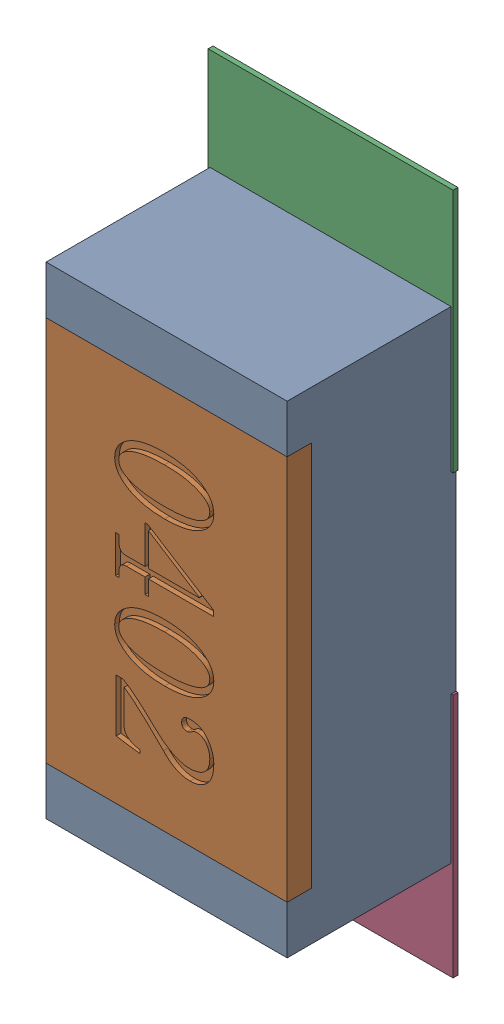
SolidWorks assembly R16, configuration Défaut. Lengths in mm.
Overall size (0.51 1.42 0.35).
5 component instances, 2 part files, 0 mates.
Components (placement in the parent):
- R0402-1: R0402 [Défaut] at (36.1371 -37.3254 0) x (0 -1 0) z (0 0 1) size (1 0.5 0.35)
- 6504207776-1: 6504207776 [Défaut] at (36.1372 -36.8683 0) size (0.51 0.51 0.01)
  - Extruded-1: Extruded [Défaut] at origin size (0.51 0.51 0.01)
- 6504207776-2: 6504207776 [Défaut] at (36.1372 -37.7754 0) size (0.51 0.51 0.01)
  - Extruded-1: Extruded [Défaut] at origin size (0.51 0.51 0.01)
